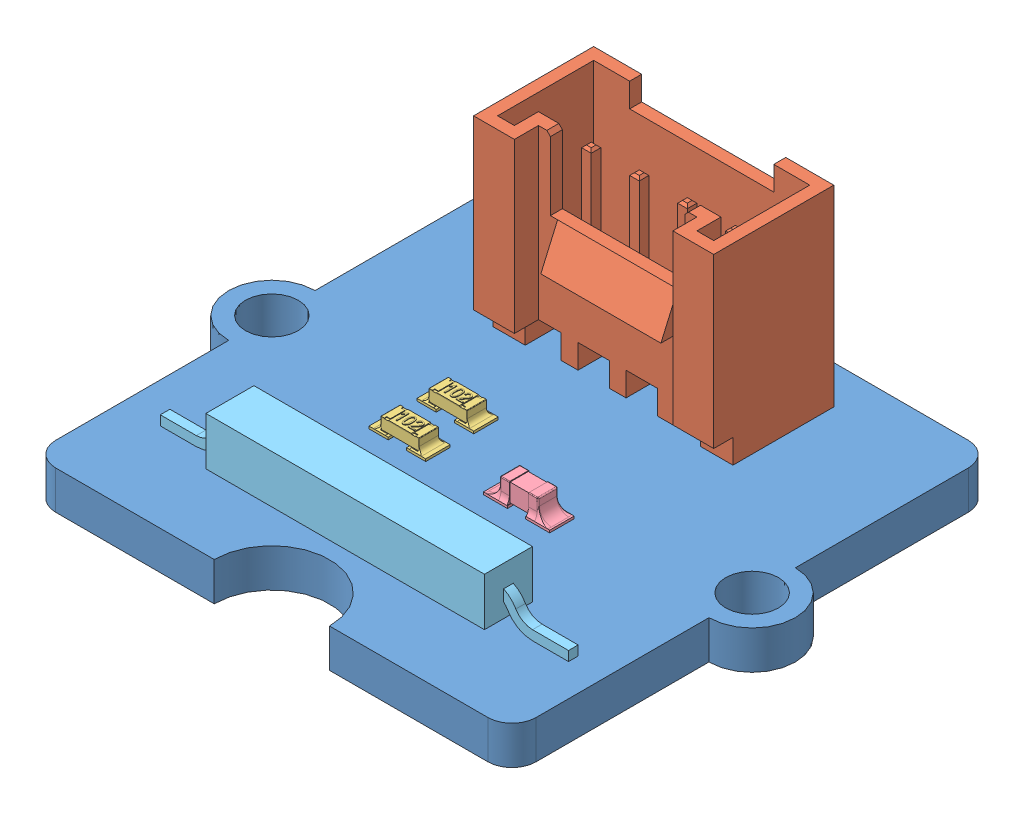
SolidWorks assembly Grove magnetic switch, configuration Défaut. Lengths in mm.
Overall size (23.6 11 20).
6 component instances, 5 part files, 9 mates.
Components (placement in the parent):
- PCB grove 20x20-1: PCB grove 20x20 [Défaut] at (-4.2327 -4.1351 -2.0377) x (0 0 1) z (-1 0 0) size (20 1.6 23.6)
- Connecteur Grove (droit)-1: Connecteur Grove (droit) [Défaut] at (-4.2327 -2.5351 -5.4377) size (10 11 5)
- 603 resistor 102-1: 603 resistor 102 [Default] at (-6.9412 -2.5351 -0.481) size (2.36 0.62 1.03)
- 603 cap on pad-1: 603 cap on pad [Défaut] at (-1.985 -2.5351 -0.4901) size (2.76 0.91 1.12)
- 603 resistor 102-2: 603 resistor 102 [Default] at (-6.9412 -2.5351 -2.481) size (2.36 0.62 1.03)
- Reed switch-1: Reed switch [Défaut] at (-4.0738 -1.3351 4.0678) size (17 2.2 2)
Mates (geometry in assembly coordinates):
- Coïncidente3: coincident anti-aligned: plane of PCB grove 20x20-1 through (-4.2958 -2.5351 -2.0377) normal (0 1 0); plane of Connecteur Grove (droit)-1 through (-4.2958 -2.5351 -5.4377) normal (0 -1 0)
- Distance2: distance = 1.6 mm aligned: plane of PCB grove 20x20-1 through (-4.2327 -2.5351 -12.0377) normal (0 0 -1); plane of Connecteur Grove (droit)-1 through (-9.2327 5.4649 -10.4377) normal (0 0 -1)
- Distance3: distance = 5 mm aligned: plane of Connecteur Grove (droit)-1 through (0.7673 5.4649 -10.4377) normal (1 0 0); plane of PCB grove 20x20-1 through (5.7673 -2.5351 -2.0377) normal (1 0 0)
- Coïncidente4: coincident: plane of PCB grove 20x20-1 through (-4.2327 -2.5351 -2.0377) normal (0 1 0); plane of 603 cap on pad-1 through (-1.985 -2.5351 -0.4901) normal (0 -1 0)
- Verrouiller1: lock: unknown of ?; unknown of ?
- Verrouiller2: lock: unknown of ?; unknown of ?
- Coïncidente5: coincident: plane of PCB grove 20x20-1 through (-4.2958 -2.5351 -2.0377) normal (0 1 0); plane of Reed switch-1 through (2.8631 -2.5351 3.8678) normal (0 -1 0)
- Verrouiller3: lock: unknown of PCB grove 20x20-1; unknown of Reed switch-1
- Verrouiller4: lock: unknown of PCB grove 20x20-1; unknown of 603 cap on pad-1
